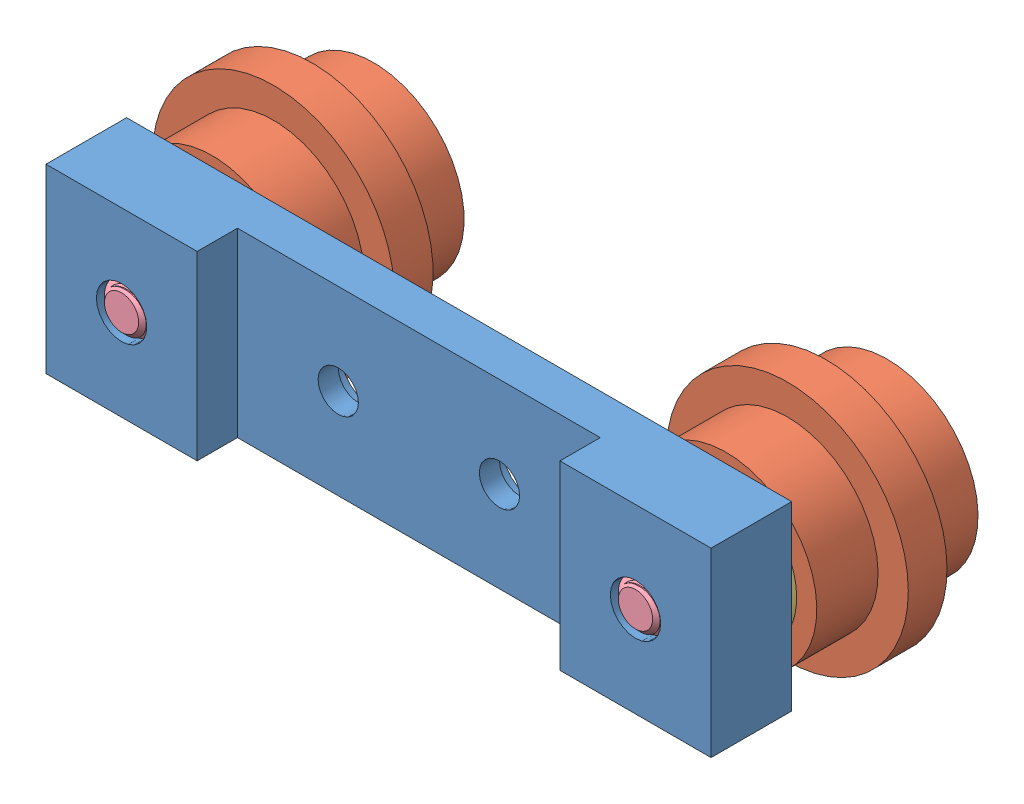
SolidWorks assembly CustomRollerAssy, configuration Default. Lengths in mm.
Overall size (122.14 42.23 41.78).
7 component instances, 4 part files, 8 mates.
Components (placement in the parent):
- Part4-1: Part4 [Default] at origin size (104.77 28.57 12.7)
- Part5-1: Part5 [Default] at (40.4813 14.2875 -1.5748) x (0.993357 -0.115071 0) z (0 0 1) size (38.1 38.1 25.4)
- Part5-2: Part5 [Default] at (-40.4813 14.2875 -1.5748) x (0.998493 -0.054888 0) z (0 0 1) size (38.1 38.1 25.4)
- Part6-1: Part6 [Default] at (40.4813 14.2875 -1.5748) x (1 0 0) z (0 -1 0) size (22.23 1.57 22.23)
- Part6-2: Part6 [Default] at (-40.4813 14.2875 0) x (1 0 0) z (0 1 0) size (22.23 1.57 22.23)
- Part8-1: Part8 [91259A623] at (40.4813 14.2875 -22.225) x (1 0 0) z (0 1 0) size (14.29 41.78 14.29)
- Part8-2: Part8 [91259A623] at (-40.4813 14.2875 -22.225) x (1 0 0) z (0 1 0) size (14.29 41.78 14.29)
Mates (geometry in assembly coordinates):
- Coincident3: coincident anti-aligned: plane of Part4-1 through (-52.3875 28.575 0) normal (0 0 -1); plane of Part6-1 through (40.4813 14.2875 0) normal (0 0 1)
- Coincident4: coincident anti-aligned: plane of Part4-1 through (-52.3875 28.575 0) normal (0 0 -1); plane of Part6-2 through (-40.4813 14.2875 0) normal (0 0 1)
- Coincident5: coincident anti-aligned: plane of Part5-2 through (-40.4813 14.2875 -1.5748) normal (0 0 1); plane of Part6-2 through (-40.4813 14.2875 -1.5748) normal (0 0 -1)
- Coincident6: coincident anti-aligned: plane of Part5-1 through (40.4813 14.2875 -1.5748) normal (0 0 1); plane of Part6-1 through (40.4813 14.2875 -1.5748) normal (0 0 -1)
- Concentric8: concentric: cylinder of Part4-1 through (-40.4813 14.2875 12.7) axis (0 0 1) radius 3.9688; cylinder of Part8-2 through (-40.4813 14.2875 -22.225) axis (0 0 1) radius 4.7625
- Concentric9: concentric: cylinder of Part4-1 through (40.4813 14.2875 12.7) axis (0 0 1) radius 3.9688; cylinder of Part8-1 through (40.4813 14.2875 -22.225) axis (0 0 1) radius 4.7625
- Coincident7: coincident anti-aligned: plane of Part4-1 through (-52.3875 28.575 0) normal (0 0 -1); plane of Part8-2 through (-40.4813 14.2875 0) normal (0 0 1)
- Coincident8: coincident anti-aligned: plane of Part4-1 through (-52.3875 28.575 0) normal (0 0 -1); plane of Part8-1 through (40.4813 14.2875 0) normal (0 0 1)
